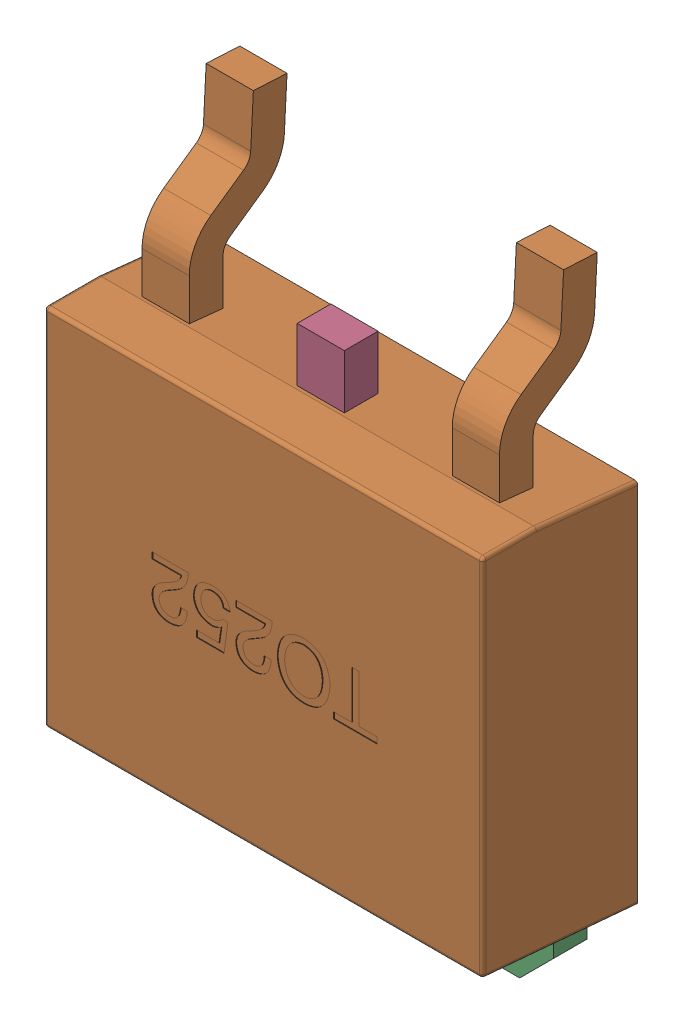
SolidWorks assembly MBG1, configuration 默认. Lengths in mm.
Overall size (6.5 9.42 2.31).
3 component instances, 2 part files, 0 mates.
Components (placement in the parent):
- TO252-1: TO252 [默认] at (79.516 45.7069 0) x (-1 0 0) z (0 0 1) size (6.5 9.42 2.31)
  - LOGO_-1: LOGO_ [默认] at (2.3503 3.4211 -0.0025) x (-1 0 0) z (0 0 -1) size (0.75 0.87 0.01)
  - TO252-1: TO252 [默认] at origin size (6.5 9.42 2.3)
